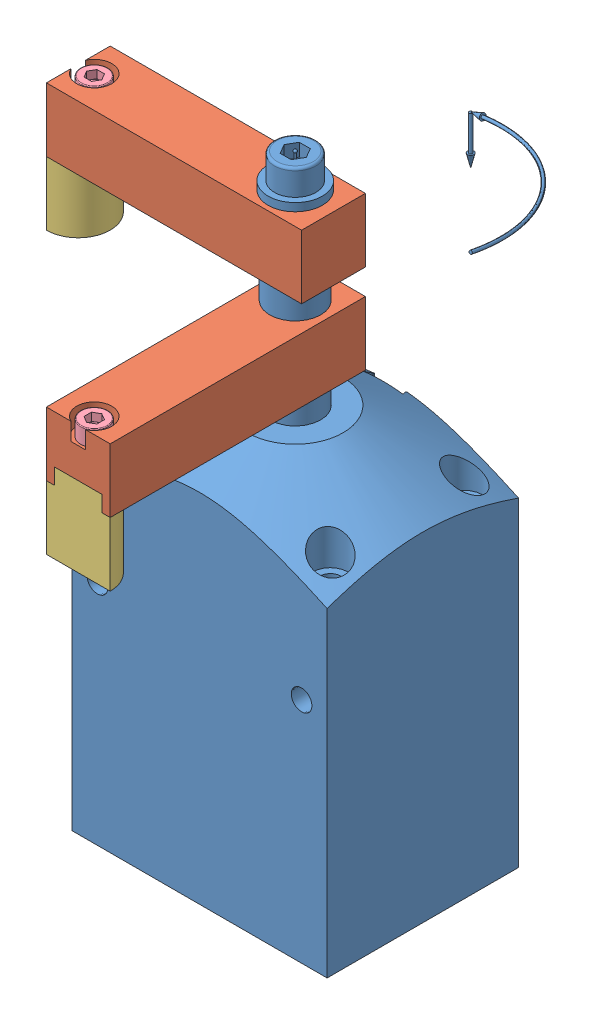
SolidWorks assembly assemb_pneu_clamp_v1, configuration Default. Lengths in mm.
Overall size (123.53 190.01 124).
9 component instances, 4 part files, 6 mates.
Components (placement in the parent):
- clamping_body_ccw-1: clamping_body_ccw [Default] at (54.8293 192.6837 163.8964) x (-1 0 0) z (0 1 0) size (95.58 86.05 190.01)
- assemb_braco_v1-1: assemb_braco_v1 [Default] at (54.1161 128.0797 225.0616) x (-1 0 0) z (0 0 -1) size (80 40 20)
  - clamping_arm_sp_v1-2: clamping_arm_sp_v1 [Default] at (-0.7132 54.1041 61.1653) x (1 0 0) z (0 1 0) size (80 20 20)
  - contact_end_half-1: contact_end_half [Default] at (67.2868 14.1041 61.1653) size (10 25 20)
  - socket head cap screw_iso-2: socket head cap screw_iso [ISO 4762 M5 x 16 - 16N] at (62.2868 53.6041 61.1653) x (0 -1 0) z (0 0 1) size (21 8.5 8.5)
- assemb_braco_v1-2: assemb_braco_v1 [Default] at (115.9945 98.0797 164.6096) x (0 0 1) z (-1 0 0) size (80 40 20)
  - clamping_arm_sp_v1-2: clamping_arm_sp_v1 [Default] at (-0.7132 54.1041 61.1653) x (1 0 0) z (0 1 0) size (80 20 20)
  - contact_end_half-1: contact_end_half [Default] at (67.2868 14.1041 61.1653) size (10 25 20)
  - socket head cap screw_iso-2: socket head cap screw_iso [ISO 4762 M5 x 16 - 16N] at (62.2868 53.6041 61.1653) x (0 -1 0) z (0 0 1) size (21 8.5 8.5)
Mates (geometry in assembly coordinates):
- Concentric1: concentric aligned: cone of clamping_body_ccw-1 through (54.8293 180.1837 163.8964) axis (0 1 0); cone of assemb_braco_v1-1/clamping_arm_sp_v1-2 through (54.8293 182.1837 163.8964) axis (0 1 0)
- Parallel1: parallel aligned: plane of clamping_body_ccw-1 through (14.8293 123.6837 133.8964) normal (-1 0 0); plane of assemb_braco_v1-1/clamping_arm_sp_v1-2 through (-13.1707 167.1837 156.3964) normal (-1 0 0)
- Coincident2: coincident aligned: circle of clamping_body_ccw-1; plane of assemb_braco_v1-1/clamping_arm_sp_v1-2 through (66.8293 162.1837 153.8964) normal (0 -1 0)
- Concentric2: concentric aligned: cylinder of clamping_body_ccw-1 through (54.8293 122.705 163.8964) axis (0 -1 0) radius 8; circle of assemb_braco_v1-2/clamping_arm_sp_v1-2
- Parallel2: parallel aligned: plane of clamping_body_ccw-1 through (94.8293 123.6837 193.8964) normal (0 0 1); plane of assemb_braco_v1-2/clamping_arm_sp_v1-2 through (47.3293 137.1837 231.8964) normal (0 0 1)
- Distance1: distance = 30 mm aligned: plane of assemb_braco_v1-2/clamping_arm_sp_v1-2 through (44.8293 152.1837 151.8964) normal (0 1 0); plane of assemb_braco_v1-1/clamping_arm_sp_v1-2 through (66.8293 182.1837 153.8964) normal (0 1 0)
